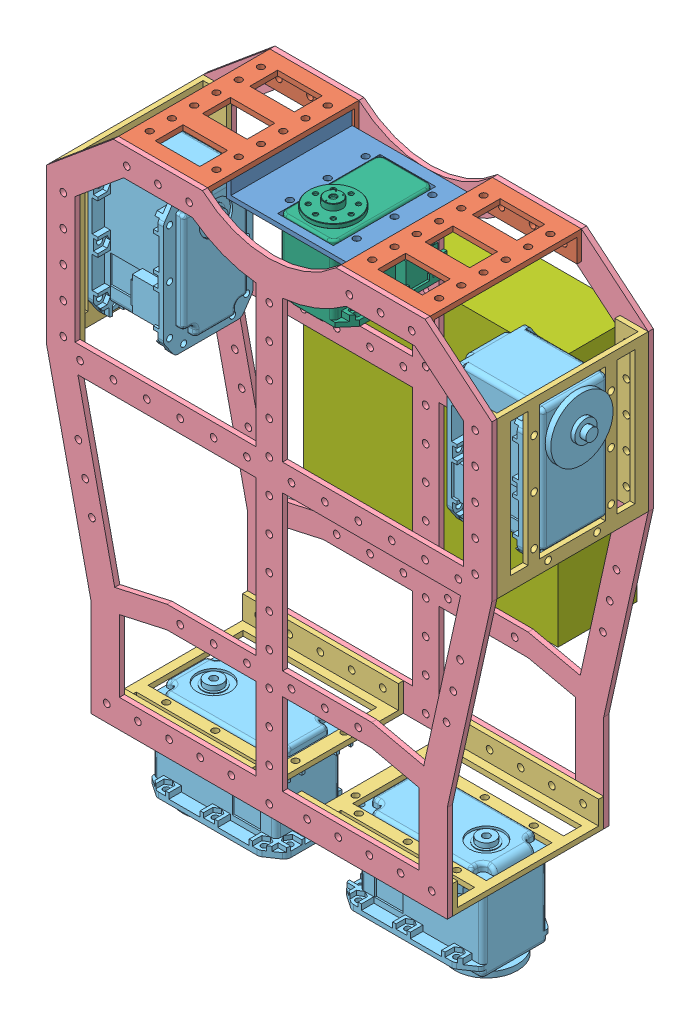
SolidWorks assembly torso, configuration Default. Lengths in mm.
Overall size (217.43 273.5 112.95).
15 component instances, 7 part files, 45 mates.
Components (placement in the parent):
- torso_frame_head-1: torso_frame_head [Default] at (0 -3.827 -35) size (76 8 58.5)
- torso_frame_link-1: torso_frame_link [Default] at (-50 -6.241 0) x (0 0 1) z (-1 0 0) size (75.11 12.7 53.47)
- torso_frame_motor-1: torso_frame_motor [Default] at (-98.857 -88.541 0) x (0 0 1) z (-1 0 0) size (68 70 36.25)
- torso_main-1: torso_main [Default] at (0 0 34) size (200 228.5 2.29)
- torso_main-2: torso_main [Default] at (0 0 -36.286) size (200 228.5 2.29)
- torso_frame_link-2: torso_frame_link [Default] at (50 -6.241 0) x (0 0 1) z (-1 0 0) size (75.11 12.7 53.47)
- torso_frame_motor-2: torso_frame_motor [Default] at (98.857 -88.541 0) x (0 0 -1) z (1 0 0) size (68 70 36.25)
- torso_frame_motor-3: torso_frame_motor [Default] at (10 -220.898 0) x (0 0 -1) z (0 -1 0) size (68 70 36.25)
- torso_frame_motor-4: torso_frame_motor [Default] at (-10 -220.898 0) x (0 0 1) z (0 -1 0) size (68 70 36.25)
- MX-64T_step-1: MX-64T_step [Default] at (80.714 -37.291 0) x (0 0 -1) z (1 0 0) size (40.2 62.1 50)
- MX-64T_step-2: MX-64T_step [Default] at (-80.714 -37.291 0) x (0 0 1) z (-1 0 0) size (40.2 62.1 50)
- MX-64T_step-3: MX-64T_step [Default] at (61.25 -239.041 0) x (0 0 -1) z (0 -1 0) size (40.2 62.1 50)
- MX-64T_step-4: MX-64T_step [Default] at (-61.25 -239.041 0) x (0 0 1) z (0 -1 0) size (40.2 62.1 50)
- MX28_step-1: MX28_step [Default] at (11.9078 -61.4181 -29.7938) x (-1 0 0) z (0 1 0) size (35.6 50.71 42.6)
- nuc-1: nuc [Default] at (0 -108.0269 -54.066) size (114.3 111.76 35.56)
Mates (geometry in assembly coordinates):
- Concentric1: concentric aligned: cylinder of torso_frame_link-1 through (-64 -1.034 34) axis (0 0 1) radius 1.5; cylinder of torso_main-1 through (-64 -1.034 36.286) axis (0 0 1) radius 1.5
- Concentric2: concentric aligned: cylinder of torso_frame_link-1 through (-36 -1.034 34) axis (0 0 1) radius 1.5; cylinder of torso_main-1 through (-36 -1.034 36.286) axis (0 0 1) radius 1.5
- Coincident1: coincident anti-aligned: plane of torso_frame_link-1 through (-70 -6.241 34) normal (0 0 1); plane of torso_main-1 through (0 40 34) normal (0 0 -1)
- Concentric3: concentric aligned: cylinder of torso_frame_link-1 through (-64 -1.034 34) axis (0 0 1) radius 1.5; cylinder of torso_main-2 through (-64 -1.034 -34) axis (0 0 1) radius 1.5
- Concentric4: concentric aligned: cylinder of torso_frame_link-1 through (-36 -1.034 34) axis (0 0 1) radius 1.5; cylinder of torso_main-2 through (-36 -1.034 -34) axis (0 0 1) radius 1.5
- Coincident2: coincident anti-aligned: plane of torso_frame_link-1 through (-70 -6.241 -34) normal (0 0 -1); plane of torso_main-2 through (0 40 -34) normal (0 0 1)
- Concentric5: concentric aligned: cylinder of torso_frame_motor-1 through (-92.507 -25.541 -34) axis (0 0 -1) radius 1.5; cylinder of torso_main-2 through (-92.507 -25.541 -36.286) axis (0 0 -1) radius 1.5
- Concentric6: concentric aligned: cylinder of torso_frame_motor-1 through (-92.507 -81.541 -34) axis (0 0 -1) radius 1.5; cylinder of torso_main-2 through (-92.507 -81.541 -36.286) axis (0 0 -1) radius 1.5
- Coincident3: coincident anti-aligned: plane of torso_frame_motor-1 through (-97.714 -88.541 -34) normal (0 0 -1); plane of torso_main-2 through (0 40 -34) normal (0 0 1)
- Coincident4: coincident anti-aligned: plane of torso_frame_head-1 through (-30 4.173 15) normal (0 1 0); plane of torso_frame_link-1 through (-70 4.173 -32) normal (0 -1 0)
- Concentric9: concentric aligned: cylinder of torso_main-2 through (36 -1.034 -34) axis (0 0 1) radius 1.5; cylinder of torso_frame_link-2 through (36 -1.034 34) axis (0 0 1) radius 1.5
- Concentric10: concentric aligned: cylinder of torso_main-2 through (64 -1.034 -34) axis (0 0 1) radius 1.5; cylinder of torso_frame_link-2 through (64 -1.034 34) axis (0 0 1) radius 1.5
- Coincident5: coincident anti-aligned: plane of torso_main-2 through (0 40 -34) normal (0 0 1); plane of torso_frame_link-2 through (30 -6.241 -34) normal (0 0 -1)
- Concentric11: concentric anti-aligned: cylinder of torso_main-1 through (92.507 -25.541 34) axis (0 0 -1) radius 1.5; cylinder of torso_frame_motor-2 through (92.507 -25.541 34) axis (0 0 1) radius 1.5
- Concentric12: concentric anti-aligned: cylinder of torso_main-1 through (92.507 -81.541 34) axis (0 0 -1) radius 1.5; cylinder of torso_frame_motor-2 through (92.507 -81.541 34) axis (0 0 1) radius 1.5
- Coincident6: coincident anti-aligned: plane of torso_main-1 through (0 40 34) normal (0 0 -1); plane of torso_frame_motor-2 through (97.714 -88.541 34) normal (0 0 1)
- Concentric13: concentric aligned: cylinder of torso_main-2 through (-73 -214.548 -36.286) axis (0 0 -1) radius 1.5; cylinder of torso_frame_motor-4 through (-73 -214.548 -34) axis (0 0 -1) radius 1.5
- Concentric14: concentric aligned: cylinder of torso_main-2 through (-17 -214.548 -36.286) axis (0 0 -1) radius 1.5; cylinder of torso_frame_motor-4 through (-17 -214.548 -34) axis (0 0 -1) radius 1.5
- Coincident7: coincident anti-aligned: plane of torso_main-2 through (0 40 -34) normal (0 0 1); plane of torso_frame_motor-4 through (-10 -219.755 -34) normal (0 0 -1)
- Concentric15: concentric anti-aligned: cylinder of torso_main-2 through (73 -214.548 -36.286) axis (0 0 -1) radius 1.5; cylinder of torso_frame_motor-3 through (73 -214.548 34) axis (0 0 1) radius 1.5
- Concentric16: concentric anti-aligned: cylinder of torso_main-2 through (17 -214.548 -36.286) axis (0 0 -1) radius 1.5; cylinder of torso_frame_motor-3 through (17 -214.548 34) axis (0 0 1) radius 1.5
- Coincident8: coincident anti-aligned: plane of torso_main-2 through (0 40 -34) normal (0 0 1); plane of torso_frame_motor-3 through (10 -219.755 -34) normal (0 0 -1)
- Concentric25: concentric aligned: cylinder of torso_frame_head-1 through (35 4.173 -25) axis (0 1 0) radius 1.5; cylinder of torso_frame_link-2 through (35 6.459 -25) axis (0 1 0) radius 1.5
- Concentric26: concentric aligned: cylinder of torso_frame_head-1 through (35 4.173 -5) axis (0 1 0) radius 1.5; cylinder of torso_frame_link-2 through (35 6.459 -5) axis (0 1 0) radius 1.5
- Concentric29: concentric aligned: cylinder of torso_frame_motor-2 through (100 -33.291 -17.3) axis (-1 0 0) radius 1.5; cylinder of MX-64T_step-1 through (80.714 -33.291 -17.3) axis (-1 0 0) radius 1.35
- Concentric30: concentric aligned: cylinder of torso_frame_motor-2 through (100 -55.291 -17.3) axis (-1 0 0) radius 1.5; cylinder of MX-64T_step-1 through (80.714 -55.291 -17.3) axis (-1 0 0) radius 1.35
- Coincident10: coincident anti-aligned: plane of torso_frame_motor-2 through (97.714 -88.541 0) normal (-1 0 0); plane of MX-64T_step-1 through (97.714 -37.291 0) normal (1 0 0)
- Concentric31: concentric aligned: cylinder of torso_frame_motor-1 through (-100 -33.291 -17.3) axis (1 0 0) radius 1.5; cylinder of MX-64T_step-2 through (-80.714 -33.291 -17.3) axis (1 0 0) radius 1.35
- Concentric32: concentric aligned: cylinder of torso_frame_motor-1 through (-100 -33.291 17.3) axis (1 0 0) radius 1.5; cylinder of MX-64T_step-2 through (-80.714 -33.291 17.3) axis (1 0 0) radius 1.35
- Coincident11: coincident anti-aligned: plane of torso_frame_motor-1 through (-97.714 -88.541 0) normal (1 0 0); plane of MX-64T_step-2 through (-97.714 -37.291 0) normal (-1 0 0)
- Concentric33: concentric aligned: cylinder of torso_frame_motor-4 through (-65.25 -222.041 -17.3) axis (0 1 0) radius 1.5; cylinder of MX-64T_step-4 through (-65.25 -239.041 -17.3) axis (0 1 0) radius 1.35
- Concentric34: concentric aligned: cylinder of torso_frame_motor-4 through (-65.25 -222.041 17.3) axis (0 1 0) radius 1.5; cylinder of MX-64T_step-4 through (-65.25 -239.041 17.3) axis (0 1 0) radius 1.35
- Concentric36: concentric aligned: cylinder of torso_frame_motor-3 through (65.25 -222.041 17.3) axis (0 1 0) radius 1.5; cylinder of MX-64T_step-3 through (65.25 -239.041 17.3) axis (0 1 0) radius 1.35
- Concentric37: concentric aligned: cylinder of torso_frame_motor-3 through (65.25 -222.041 -17.3) axis (0 1 0) radius 1.5; cylinder of MX-64T_step-3 through (65.25 -239.041 -17.3) axis (0 1 0) radius 1.35
- Concentric38: concentric anti-aligned: cylinder of torso_frame_head-1 through (-15 -1.827 12) axis (0 1 0) radius 1.5; cylinder of MX28_step-1 through (-15 -18.827 12) axis (0 -1 0) radius 1.35
- Concentric39: concentric anti-aligned: cylinder of torso_frame_head-1 through (15 -1.827 12) axis (0 1 0) radius 1.5; cylinder of MX28_step-1 through (15 -18.827 12) axis (0 -1 0) radius 1.35
- Coincident15: coincident anti-aligned: plane of torso_frame_head-1 through (-32 -3.827 15) normal (0 -1 0); plane of MX28_step-1 through (0 -3.827 7.5) normal (0 1 0)
- Coincident16: coincident anti-aligned: plane of torso_frame_motor-4 through (-10 -222.041 0) normal (0 -1 0); plane of MX-64T_step-4 through (-61.25 -222.041 0) normal (0 1 0)
- Coincident17: coincident anti-aligned: plane of torso_frame_motor-3 through (10 -222.041 0) normal (0 -1 0); plane of MX-64T_step-3 through (61.25 -222.041 0) normal (0 1 0)
- Distance1: distance = 34 mm anti-aligned: plane of torso_main-1 through (0 40 34) normal (0 0 -1); plane of assembly through (0 0 0) normal (0 0 1)
- Coincident19: coincident aligned: plane of torso_main-1 through (0 0 34) normal (1 0 0); plane of assembly through (0 0 0) normal (1 0 0)
- Coincident20: coincident aligned: plane of torso_main-1 through (0 0 34) normal (0 1 0); plane of assembly through (0 0 0) normal (0 1 0)
- Coincident21: coincident: plane of torso_main-2 through (0 40 -36.286) normal (0 0 -1); plane of nuc-1 through (2.0891 -132.9109 -49.5693) normal (0 0 1)
- Coincident22: coincident: plane of torso_frame_head-1 through (0 -3.827 -35) normal (1 0 0); plane of nuc-1 through (2.0891 -132.9109 -67.3493) normal (1 0 0)
- Coincident23: coincident: plane of nuc-1 through (-57.15 -52.1469 -36.286) normal (0 1 0); line of assembly
